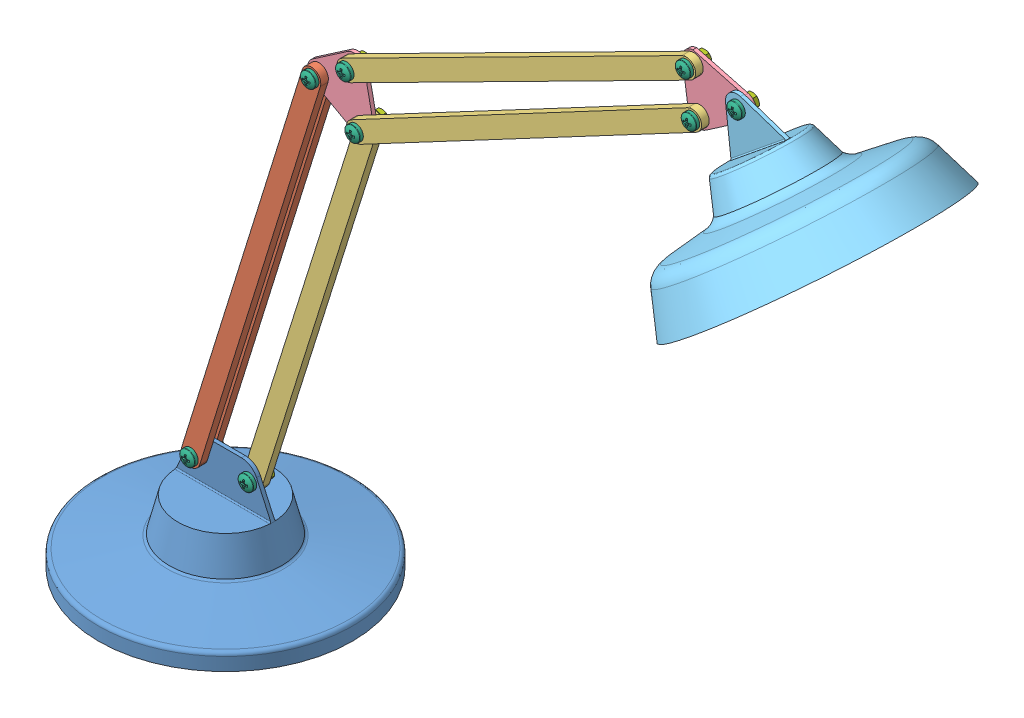
SolidWorks assembly Assem1, configuration Default. Lengths in mm.
Overall size (646.94 590.51 203).
25 component instances, 7 part files, 55 mates.
Components (placement in the parent):
- voet_steun-1: voet_steun [Default] at (63.969 54.1096 165.1081) size (200 83 200)
- strip_lang-1: strip_lang [Default] at (91.5082 276.884 157.6081) x (0.29712 0.95484 0) z (0 0 1) size (335 15 6)
- strip_lang-2: strip_lang [Default] at (91.5082 276.884 166.6081) x (0.29712 0.95484 0) z (0 0 1) size (335 15 6)
- strip_kort-1: strip_kort [Default] at (129.0019 267.1901 157.6081) x (0.300219 0.95387 0) z (0 0 1) size (315 15 6)
- driehoek-1: driehoek [Default] at (166.7085 448.6285 163.6081) x (0.874684 -0.484694 0) z (0 0 1) size (58 47.99 3)
- strip_kort-2: strip_kort [Default] at (300.5149 516.4212 166.6081) x (0.892043 0.451951 0) z (0 0 1) size (315 15 6)
- strip_kort-3: strip_kort [Default] at (306.5072 480.6343 166.6081) x (0.88315 0.469091 0) z (0 0 1) size (315 15 6)
- driehoek-2: driehoek [Default] at (434.3213 584.2139 163.6081) x (0.823646 0.567104 0) z (0 0 1) size (58 47.99 3)
- lampen_kap-1: lampen_kap [Default] at (533.3712 498.2422 168.1081) x (0.775355 0.631525 0) z (0 0 1) size (200 107.34 200)
- pan head cross recess screw_iso-4: pan head cross recess screw_iso [ISO 7045 - M6 x 20 - Z - 20N] at (43.969 124.1096 177.2081) x (0 0 -1) z (1 0 0) size (24.48 12 12)
- pan head cross recess screw_iso-5: pan head cross recess screw_iso [ISO 7045 - M6 x 16 - Z - 16N] at (83.969 124.1096 171.2081) x (0 0 -1) z (1 0 0) size (20.48 12 12)
- pan head cross recess screw_iso-6: pan head cross recess screw_iso [ISO 7045 - M6 x 20 - Z - 20N] at (139.0474 429.6584 177.2081) x (0 0 -1) z (1 0 0) size (24.48 12 12)
- pan head cross recess screw_iso-7: pan head cross recess screw_iso [ISO 7045 - M6 x 16 - Z - 16N] at (166.7085 448.6285 177.2081) x (0 0 -1) z (1 0 0) size (20.48 12 12)
- pan head cross recess screw_iso-8: pan head cross recess screw_iso [ISO 7045 - M6 x 20 - Z - 20N] at (174.0348 410.2706 177.2081) x (0 0 -1) z (1 0 0) size (24.48 12 12)
- pan head cross recess screw_iso-10: pan head cross recess screw_iso [ISO 7045 - M6 x 16 - Z - 16N] at (434.3213 584.2139 177.2081) x (0 0 -1) z (1 0 0) size (20.48 12 12)
- pan head cross recess screw_iso-11: pan head cross recess screw_iso [ISO 7045 - M6 x 20 - Z - 20N] at (438.9797 550.998 177.2081) x (0 0 -1) z (1 0 0) size (24.48 12 12)
- pan head cross recess screw_iso-12: pan head cross recess screw_iso [ISO 7045 - M6 x 12 - Z - 12N] at (471.9256 573.6821 174.2081) x (0 0 -1) z (1 0 0) size (16.48 12 12)
- hex flange nut gradea_iso-2: hex flange nut gradea_iso [ISO - 4161 - M6 - N] at (43.969 124.1096 151.6081) x (0.923728 0.383049 0) z (0 0 -1) size (14.2 14.2 6)
- hex flange nut gradea_iso-3: hex flange nut gradea_iso [ISO - 4161 - M6 - N] at (83.969 124.1096 151.6081) x (0.923728 0.383049 0) z (0 0 -1) size (14.2 14.2 6)
- hex flange nut gradea_iso-4: hex flange nut gradea_iso [ISO - 4161 - M6 - N] at (174.0348 410.2706 151.6081) x (0.923728 0.383049 0) z (0 0 -1) size (14.2 14.2 6)
- hex flange nut gradea_iso-5: hex flange nut gradea_iso [ISO - 4161 - M6 - N] at (139.0474 429.6584 151.6081) x (0.923728 0.383049 0) z (0 0 -1) size (14.2 14.2 6)
- hex flange nut gradea_iso-6: hex flange nut gradea_iso [ISO - 4161 - M6 - N] at (166.7085 448.6285 157.6081) x (0.923728 0.383049 0) z (0 0 -1) size (14.2 14.2 6)
- hex flange nut gradea_iso-7: hex flange nut gradea_iso [ISO - 4161 - M6 - N] at (434.3213 584.2139 157.6081) x (0.923728 0.383049 0) z (0 0 -1) size (14.2 14.2 6)
- hex flange nut gradea_iso-8: hex flange nut gradea_iso [ISO - 4161 - M6 - N] at (471.9256 573.6821 157.6081) x (0.923728 0.383049 0) z (0 0 -1) size (14.2 14.2 6)
- hex flange nut gradea_iso-9: hex flange nut gradea_iso [ISO - 4161 - M6 - N] at (438.9797 550.998 157.6081) x (0.923728 0.383049 0) z (0 0 -1) size (14.2 14.2 6)
Mates (geometry in assembly coordinates):
- Concentric1: concentric anti-aligned: cylinder of voet_steun-1 through (43.969 124.1096 166.6081) axis (0 0 -1) radius 3; cylinder of strip_lang-1 through (43.969 124.1096 157.6081) axis (0 0 1) radius 3.25
- Coincident1: coincident anti-aligned: plane of voet_steun-1 through (63.969 54.1096 163.6081) normal (0 0 -1); plane of strip_lang-1 through (43.969 124.1096 163.6081) normal (0 0 1)
- Concentric2: concentric anti-aligned: cylinder of voet_steun-1 through (43.969 124.1096 166.6081) axis (0 0 -1) radius 3; cylinder of strip_lang-2 through (43.969 124.1096 166.6081) axis (0 0 1) radius 3.25
- Coincident2: coincident anti-aligned: plane of voet_steun-1 through (63.969 54.1096 166.6081) normal (0 0 1); plane of strip_lang-2 through (43.969 124.1096 166.6081) normal (0 0 -1)
- Concentric3: concentric anti-aligned: cylinder of voet_steun-1 through (83.969 124.1096 166.6081) axis (0 0 -1) radius 3; cylinder of strip_kort-1 through (83.969 124.1096 157.6081) axis (0 0 1) radius 3.25
- Coincident3: coincident anti-aligned: plane of voet_steun-1 through (63.969 54.1096 163.6081) normal (0 0 -1); plane of strip_kort-1 through (83.969 124.1096 163.6081) normal (0 0 1)
- Concentric4: concentric anti-aligned: cylinder of strip_lang-2 through (139.0474 429.6584 166.6081) axis (0 0 1) radius 3.25; cylinder of driehoek-1 through (139.0474 429.6584 166.6081) axis (0 0 -1) radius 3
- Concentric5: concentric anti-aligned: cylinder of strip_kort-1 through (174.0348 410.2706 157.6081) axis (0 0 1) radius 3.25; cylinder of driehoek-1 through (174.0348 410.2706 166.6081) axis (0 0 -1) radius 3
- Coincident4: coincident anti-aligned: plane of strip_lang-2 through (43.969 124.1096 166.6081) normal (0 0 -1); plane of driehoek-1 through (174.0348 410.2706 166.6081) normal (0 0 1)
- Coincident5: coincident anti-aligned: plane of strip_lang-1 through (43.969 124.1096 163.6081) normal (0 0 1); plane of driehoek-1 through (174.0348 410.2706 163.6081) normal (0 0 -1)
- Coincident6: coincident anti-aligned: plane of strip_kort-1 through (83.969 124.1096 163.6081) normal (0 0 1); plane of driehoek-1 through (174.0348 410.2706 163.6081) normal (0 0 -1)
- Coincident7: coincident anti-aligned: plane of strip_lang-1 through (43.969 124.1096 163.6081) normal (0 0 1); plane of driehoek-1 through (174.0348 410.2706 163.6081) normal (0 0 -1)
- Concentric6: concentric anti-aligned: cylinder of strip_lang-1 through (139.0474 429.6584 157.6081) axis (0 0 1) radius 3.25; cylinder of driehoek-1 through (139.0474 429.6584 166.6081) axis (0 0 -1) radius 3
- Concentric7: concentric anti-aligned: cylinder of driehoek-1 through (166.7085 448.6285 166.6081) axis (0 0 -1) radius 3; cylinder of strip_kort-2 through (166.7085 448.6285 166.6081) axis (0 0 1) radius 3.25
- Coincident8: coincident anti-aligned: plane of driehoek-1 through (174.0348 410.2706 166.6081) normal (0 0 1); plane of strip_kort-2 through (166.7085 448.6285 166.6081) normal (0 0 -1)
- Concentric8: concentric anti-aligned: cylinder of driehoek-1 through (174.0348 410.2706 166.6081) axis (0 0 -1) radius 3; cylinder of strip_kort-3 through (174.0348 410.2706 166.6081) axis (0 0 1) radius 3.25
- Coincident9: coincident anti-aligned: plane of driehoek-1 through (174.0348 410.2706 166.6081) normal (0 0 1); plane of strip_kort-3 through (174.0348 410.2706 166.6081) normal (0 0 -1)
- Concentric9: concentric anti-aligned: cylinder of strip_kort-3 through (438.9797 550.998 166.6081) axis (0 0 1) radius 3.25; cylinder of driehoek-2 through (438.9797 550.998 166.6081) axis (0 0 -1) radius 3
- Concentric10: concentric anti-aligned: cylinder of strip_kort-2 through (434.3213 584.2139 166.6081) axis (0 0 1) radius 3.25; cylinder of driehoek-2 through (434.3213 584.2139 166.6081) axis (0 0 -1) radius 3
- Coincident10: coincident anti-aligned: plane of strip_kort-2 through (166.7085 448.6285 166.6081) normal (0 0 -1); plane of driehoek-2 through (471.9256 573.6821 166.6081) normal (0 0 1)
- Coincident11: coincident anti-aligned: plane of strip_kort-3 through (174.0348 410.2706 166.6081) normal (0 0 -1); plane of driehoek-2 through (471.9256 573.6821 166.6081) normal (0 0 1)
- Concentric11: concentric aligned: cylinder of driehoek-2 through (471.9256 573.6821 166.6081) axis (0 0 -1) radius 3; cylinder of lampen_kap-1 through (471.9256 573.6821 169.6081) axis (0 0 -1) radius 3
- Coincident12: coincident anti-aligned: plane of driehoek-2 through (471.9256 573.6821 166.6081) normal (0 0 1); plane of lampen_kap-1 through (533.3712 498.2422 166.6081) normal (0 0 -1)
- Concentric13: concentric aligned: cylinder of strip_lang-2 through (43.969 124.1096 166.6081) axis (0 0 1) radius 3.25; cylinder of pan head cross recess screw_iso-4 through (43.969 124.1096 202.6081) axis (0 0 1) radius 6
- Coincident14: coincident anti-aligned: plane of strip_lang-2 through (43.969 124.1096 172.6081) normal (0 0 1); plane of pan head cross recess screw_iso-4 through (43.969 127.1096 172.6081) normal (0 0 -1)
- Concentric14: concentric anti-aligned: cylinder of voet_steun-1 through (83.969 124.1096 166.6081) axis (0 0 -1) radius 3; cylinder of pan head cross recess screw_iso-5 through (83.969 124.1096 196.6081) axis (0 0 1) radius 6
- Coincident15: coincident anti-aligned: plane of voet_steun-1 through (63.969 54.1096 166.6081) normal (0 0 1); plane of pan head cross recess screw_iso-5 through (83.969 127.1096 166.6081) normal (0 0 -1)
- Concentric15: concentric aligned: cylinder of strip_lang-2 through (139.0474 429.6584 166.6081) axis (0 0 1) radius 3.25; cylinder of pan head cross recess screw_iso-6 through (139.0474 429.6584 202.6081) axis (0 0 1) radius 6
- Coincident16: coincident anti-aligned: plane of strip_lang-2 through (43.969 124.1096 172.6081) normal (0 0 1); plane of pan head cross recess screw_iso-6 through (139.0474 432.6584 172.6081) normal (0 0 -1)
- Concentric16: concentric aligned: cylinder of strip_kort-2 through (166.7085 448.6285 166.6081) axis (0 0 1) radius 3.25; cylinder of pan head cross recess screw_iso-7 through (166.7085 448.6285 202.6081) axis (0 0 1) radius 6
- Coincident17: coincident anti-aligned: plane of strip_kort-2 through (166.7085 448.6285 172.6081) normal (0 0 1); plane of pan head cross recess screw_iso-7 through (166.7085 451.6285 172.6081) normal (0 0 -1)
- Concentric17: concentric aligned: cylinder of strip_kort-3 through (174.0348 410.2706 166.6081) axis (0 0 1) radius 3.25; cylinder of pan head cross recess screw_iso-8 through (174.0348 410.2706 202.6081) axis (0 0 1) radius 6
- Coincident18: coincident anti-aligned: plane of strip_kort-3 through (174.0348 410.2706 172.6081) normal (0 0 1); plane of pan head cross recess screw_iso-8 through (174.0348 413.2706 172.6081) normal (0 0 -1)
- Concentric18: concentric aligned: cylinder of strip_kort-2 through (434.3213 584.2139 166.6081) axis (0 0 1) radius 3.25; cylinder of pan head cross recess screw_iso-10 through (434.3213 584.2139 202.6081) axis (0 0 1) radius 6
- Coincident19: coincident anti-aligned: plane of strip_kort-2 through (166.7085 448.6285 172.6081) normal (0 0 1); plane of pan head cross recess screw_iso-10 through (434.3213 587.2139 172.6081) normal (0 0 -1)
- Concentric19: concentric aligned: cylinder of strip_kort-3 through (438.9797 550.998 166.6081) axis (0 0 1) radius 3.25; cylinder of pan head cross recess screw_iso-11 through (438.9797 550.998 202.6081) axis (0 0 1) radius 6
- Coincident20: coincident anti-aligned: plane of strip_kort-3 through (174.0348 410.2706 172.6081) normal (0 0 1); plane of pan head cross recess screw_iso-11 through (438.9797 553.998 172.6081) normal (0 0 -1)
- Concentric20: concentric anti-aligned: cylinder of lampen_kap-1 through (471.9256 573.6821 169.6081) axis (0 0 -1) radius 3; cylinder of pan head cross recess screw_iso-12 through (471.9256 573.6821 199.6081) axis (0 0 1) radius 6
- Coincident21: coincident anti-aligned: plane of lampen_kap-1 through (533.3712 498.2422 169.6081) normal (0 0 1); plane of pan head cross recess screw_iso-12 through (471.9256 576.6821 169.6081) normal (0 0 -1)
- Concentric21: concentric anti-aligned: cylinder of strip_lang-1 through (43.969 124.1096 157.6081) axis (0 0 1) radius 3.25; cylinder of hex flange nut gradea_iso-2 through (43.969 124.1096 176.6456) axis (0 0 -1) radius 3
- Coincident22: coincident anti-aligned: plane of strip_lang-1 through (43.969 124.1096 157.6081) normal (0 0 -1); plane of hex flange nut gradea_iso-2 through (46.1805 118.7764 157.6081) normal (0 0 1)
- Concentric22: concentric anti-aligned: cylinder of strip_kort-1 through (83.969 124.1096 157.6081) axis (0 0 1) radius 3.25; cylinder of hex flange nut gradea_iso-3 through (83.969 124.1096 176.6456) axis (0 0 -1) radius 3
- Coincident23: coincident anti-aligned: plane of strip_kort-1 through (83.969 124.1096 157.6081) normal (0 0 -1); plane of hex flange nut gradea_iso-3 through (86.1805 118.7764 157.6081) normal (0 0 1)
- Concentric23: concentric anti-aligned: cylinder of strip_kort-1 through (174.0348 410.2706 157.6081) axis (0 0 1) radius 3.25; cylinder of hex flange nut gradea_iso-4 through (174.0348 410.2706 176.6456) axis (0 0 -1) radius 3
- Coincident24: coincident anti-aligned: plane of strip_kort-1 through (83.969 124.1096 157.6081) normal (0 0 -1); plane of hex flange nut gradea_iso-4 through (176.2463 404.9375 157.6081) normal (0 0 1)
- Concentric24: concentric anti-aligned: cylinder of strip_lang-1 through (139.0474 429.6584 157.6081) axis (0 0 1) radius 3.25; cylinder of hex flange nut gradea_iso-5 through (139.0474 429.6584 176.6456) axis (0 0 -1) radius 3
- Coincident25: coincident anti-aligned: plane of strip_lang-1 through (43.969 124.1096 157.6081) normal (0 0 -1); plane of hex flange nut gradea_iso-5 through (141.259 424.3253 157.6081) normal (0 0 1)
- Concentric25: concentric aligned: cylinder of driehoek-1 through (166.7085 448.6285 166.6081) axis (0 0 -1) radius 3; cylinder of hex flange nut gradea_iso-6 through (166.7085 448.6285 182.6456) axis (0 0 -1) radius 3
- Coincident26: coincident anti-aligned: plane of driehoek-1 through (174.0348 410.2706 163.6081) normal (0 0 -1); plane of hex flange nut gradea_iso-6 through (168.92 443.2954 163.6081) normal (0 0 1)
- Concentric26: concentric aligned: cylinder of driehoek-2 through (434.3213 584.2139 166.6081) axis (0 0 -1) radius 3; cylinder of hex flange nut gradea_iso-7 through (434.3213 584.2139 182.6456) axis (0 0 -1) radius 3
- Coincident27: coincident anti-aligned: plane of driehoek-2 through (471.9256 573.6821 163.6081) normal (0 0 -1); plane of hex flange nut gradea_iso-7 through (436.5328 578.8808 163.6081) normal (0 0 1)
- Concentric27: concentric aligned: cylinder of driehoek-2 through (471.9256 573.6821 166.6081) axis (0 0 -1) radius 3; cylinder of hex flange nut gradea_iso-8 through (471.9256 573.6821 182.6456) axis (0 0 -1) radius 3
- Coincident28: coincident anti-aligned: plane of driehoek-2 through (471.9256 573.6821 163.6081) normal (0 0 -1); plane of hex flange nut gradea_iso-8 through (474.1371 568.349 163.6081) normal (0 0 1)
- Concentric28: concentric aligned: cylinder of driehoek-2 through (438.9797 550.998 166.6081) axis (0 0 -1) radius 3; cylinder of hex flange nut gradea_iso-9 through (438.9797 550.998 182.6456) axis (0 0 -1) radius 3
- Coincident29: coincident anti-aligned: plane of driehoek-2 through (471.9256 573.6821 163.6081) normal (0 0 -1); plane of hex flange nut gradea_iso-9 through (441.1912 545.6648 163.6081) normal (0 0 1)
